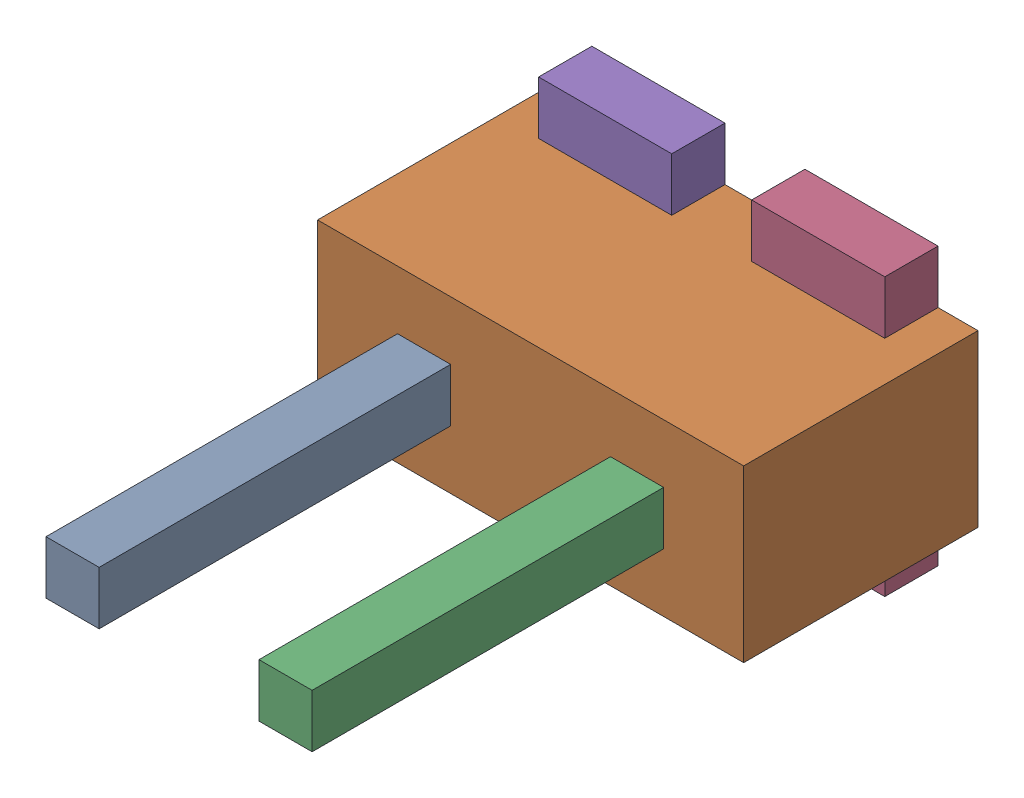
SolidWorks assembly J15, configuration ﾃﾞﾌｫﾙﾄ. Lengths in mm.
Overall size (4 2.6 5.5).
10 component instances, 3 part files, 0 mates.
Components (placement in the parent):
- 689260424-1: 689260424 [ﾃﾞﾌｫﾙﾄ] at (5.4999 54.5 2.2) size (0.5 0.5 3.3)
  - Extruded_23-1: Extruded_23 [ﾃﾞﾌｫﾙﾄ] at origin size (0.5 0.5 3.3)
- 689260560-1: 689260560 [ﾃﾞﾌｫﾙﾄ] at (6.5 54.5 0) size (4 1.6 2.2)
  - Extruded_24-1: Extruded_24 [ﾃﾞﾌｫﾙﾄ] at origin size (4 1.6 2.2)
- 689260424-2: 689260424 [ﾃﾞﾌｫﾙﾄ] at (7.4994 54.5 2.2) size (0.5 0.5 3.3)
  - Extruded_23-1: Extruded_23 [ﾃﾞﾌｫﾙﾄ] at origin size (0.5 0.5 3.3)
- 689260696-1: 689260696 [ﾃﾞﾌｫﾙﾄ] at (7.4999 54.4999 0) size (1.25 2.6 0.5)
  - Extruded_25-1: Extruded_25 [ﾃﾞﾌｫﾙﾄ] at origin size (1.25 2.6 0.5)
- 689260696-2: 689260696 [ﾃﾞﾌｫﾙﾄ] at (5.4999 54.4999 0) size (1.25 2.6 0.5)
  - Extruded_25-1: Extruded_25 [ﾃﾞﾌｫﾙﾄ] at origin size (1.25 2.6 0.5)
